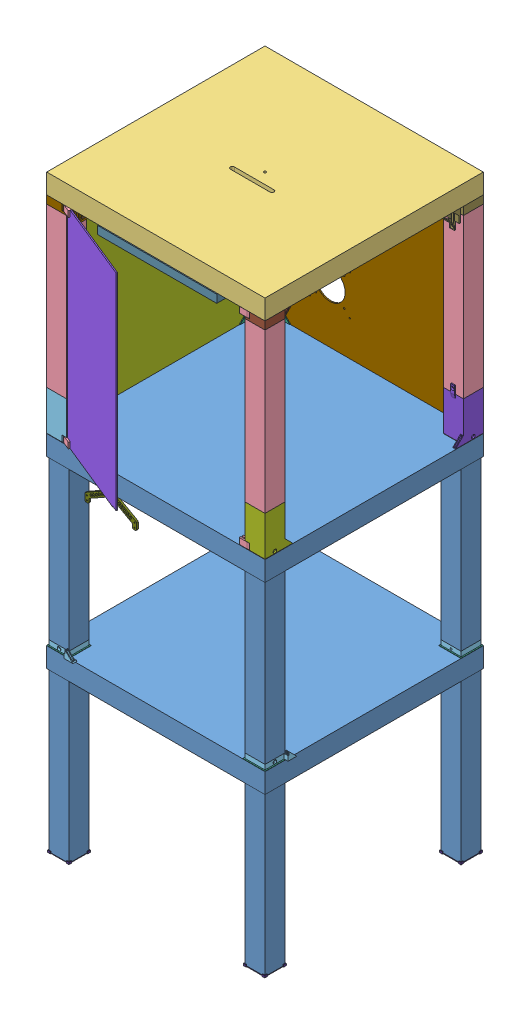
SolidWorks assembly Lack_Enclousure, configuration Predeterminado. Lengths in mm.
Overall size (564.62 1485.45 641.06).
45 component instances, 27 part files, 74 mates.
Components (placement in the parent):
- Lack_table_v3-1: Lack_table_v3 [Predeterminado] at (-27.833 176.929 550) size (550 450 550)
- Lack_table_v3-2: Lack_table_v3 [Predeterminado] at (-27.833 639.729 550) size (550 450 550)
- PSU_Holder-1: PSU_Holder [Predeterminado] at (-246.7267 603.8361 312.8336) x (0.000912 0.040041 0.999198) z (-0.058524 -0.997483 0.040025) size (59 110.01 50)
- Mesa_3-1: Mesa_3 [Predeterminado] at (23.6993 1810.529 527.7704) x (1 0 0) z (0 -1 0) size (550 558.12 570)
  - Table_Top-1: Table_Top [Predeterminado] at (-92.521 118.644 550) size (550 550 50)
  - Table_Leg-1: Table_Leg [Predeterminado] at (193.9079 -225.7264 620) size (50 50 400)
  - Table_Leg-2: Table_Leg [Predeterminado] at (-299.4883 -223.2106 620) x (0 -1 0) z (0 0 1) size (50 50 400)
  - Table_Leg-3: Table_Leg [Predeterminado] at (-296.9726 270.1856 620) x (-1 0 0) z (0 0 1) size (50 50 400)
  - Table_Leg-4: Table_Leg [Predeterminado] at (196.4237 267.6699 620) x (0 1 0) z (0 0 1) size (50 50 400)
  - Bottom_Leg_Left-1: Bottom_Leg_Left [Predeterminado] at (-301.5323 272.2296 1020) size (52.6 70 120)
  - Bottom_Leg_Back-1: Bottom_Leg_Back [Predeterminado] at (-301.5323 -227.7704 1020) size (70 70 120)
  - SimetríaBottom_Leg_Left-5: SimetríaBottom_Leg_Left [Predeterminado] at (198.4677 272.2296 1020) x (-1 0 0) z (0 0 -1) size (52.6 70 120)
  - SimetríaBottom_Leg_Back-3: SimetríaBottom_Leg_Back [Predeterminado] at (198.4677 -227.7704 1020) x (-1 0 0) z (0 0 -1) size (70 70 120)
  - Top_Front-2: Top_Front [Predeterminado] at (-301.5323 272.2296 600) size (114 114 61)
  - Top_Back-2: Top_Back [Predeterminado] at (-301.5323 -227.7704 600) x (0 1 0) z (0 0 1) size (114 114 61)
  - SimetríaTop_Front-3: SimetríaTop_Front [Predeterminado] at (198.4677 272.2296 600) x (-1 0 0) z (0 0 -1) size (114 114 61)
  - SimetríaTop_Back-3: SimetríaTop_Back [Predeterminado] at (198.4677 -227.7704 600) x (0 1 0) z (0 0 -1) size (114 114 61)
  - Plexi_Holder-1: Plexi_Holder [Predeterminado] at (172.5677 -250.9704 600) x (-1 0 0) z (0 -1 0) size (25.9 25 15.72)
- Draft_Sheet_Holder-1: Draft_Sheet_Holder [Predeterminado] at (-133.7686 1178.8709 485) size (300 20 340)
- LCD_Holder_base-1: LCD_Holder_base [Predeterminado] at (-144.833 639.729 703) size (20 10 122)
- LCD_Holder-1: LCD_Holder [Predeterminado] at (-144.4943 635.2142 806.9182) size (130 49 15)
- Bottom_Feet-1: Bottom_Feet [Predeterminado] at (-275.083 -224.271 796.75) x (1 0 0) z (0 1 0) size (54.1 54.1 30.5)
- Bottom_Feet-2: Bottom_Feet [Predeterminado] at (218.917 -224.271 797.25) x (0 0 -1) z (0 1 0) size (54.1 54.1 30.5)
- Bottom_Feet-3: Bottom_Feet [Predeterminado] at (219.417 -224.271 303.25) x (-1 0 0) z (0 1 0) size (54.1 54.1 30.5)
- Bottom_Feet-4: Bottom_Feet [Predeterminado] at (-274.583 -224.271 302.75) x (0 0 1) z (0 1 0) size (54.1 54.1 30.5)
- Bottom_Back-1: Bottom_Back [Predeterminado] at (-277.833 689.729 300) x (1 0 0) z (0 1 0) size (50 50 10.8)
- Bottom_Door-1: Bottom_Door [Predeterminado] at (-277.833 689.729 800) x (1 0 0) z (0 1 0) size (50 50 15.8)
- SimetríaBottom_Door-2: SimetríaBottom_Door [Predeterminado] at (222.167 689.729 800) x (-1 0 0) z (0 -1 0) size (50 50 15.8)
- SimetríaBottom_Back-2: SimetríaBottom_Back [Predeterminado] at (222.167 689.729 300) x (-1 0 0) z (0 -1 0) size (50 50 10.8)
- Bottom_Hinge-1: Bottom_Hinge [Predeterminado] at (-258.033 690.529 819.8) x (0.926121 0 0.377228) z (0 1 0) size (25.2 10.4 15)
- Bottom_Hinge-2: Bottom_Hinge [Predeterminado] at (202.367 690.529 819.8) x (-1 0 0) z (0 1 0) size (25.2 10.4 15)
- Table_Union_Bottom-1: Table_Union_Bottom [Predeterminado] at (-274.833 239.729 797) x (0 0 -1) z (0 -1 0) size (60.05 70 20)
- Bottom_Table_2-1: Bottom_Table_2 [Predeterminado] at (-274.833 226.929 797) x (0 0 -1) z (0 1 0) size (56 56 10.8)
- Bottom_Table_2-2: Bottom_Table_2 [Predeterminado] at (219.167 226.929 797) x (-1 0 0) z (0 1 0) size (56 56 10.8)
- Bottom_Table_2-3: Bottom_Table_2 [Predeterminado] at (219.167 226.929 303) x (0 0 1) z (0 1 0) size (56 56 10.8)
- Bottom_Table_2-4: Bottom_Table_2 [Predeterminado] at (-274.833 226.929 303) x (1 0 0) z (0 1 0) size (56 56 10.8)
- Table_Union_Bottom-5: Table_Union_Bottom [Predeterminado] at (219.167 239.729 797) x (-1 0 0) z (0 -1 0) size (60.05 70 20)
- Table_Union_Bottom-6: Table_Union_Bottom [Predeterminado] at (219.167 239.729 303) x (0 0 1) z (0 -1 0) size (60.05 70 20)
- Table_Union_Bottom-7: Table_Union_Bottom [Predeterminado] at (-274.833 239.729 303) x (1 0 0) z (0 -1 0) size (60.05 70 20)
- Bottom_Hinge-3: Bottom_Hinge [Predeterminado] at (-258.0302 1210.329 819.8028) x (0.926121 0 0.377228) z (0 -1 0) size (25.2 10.4 15)
- Bottom_Hinge-4: Bottom_Hinge [Predeterminado] at (202.3643 1210.329 819.8028) x (-1 0 0) z (0 -1 0) size (25.2 10.4 15)
- Plexi_Sides-1: Plexi_Sides [Predeterminado] at (-300.683 886.8257 513.1613) x (0 0 -1) z (1 0 0) size (450 520.8 3)
- Plexi_Holder-1: Plexi_Holder [Predeterminado] at (-300.483 1210.529 326) x (0 0 1) z (-1 0 0) size (25.9 25 15.72)
- Plexi_Door-3: Plexi_Door [Predeterminado] at (-31.0427 914.3974 910.5317) x (0.926121 0 0.377228) z (-0.377228 0 0.926121) size (222.7 520.8 3)
- Plexi_Back_80-1: Plexi_Back_80 [Predeterminado] at (9.0057 886.8257 276.95) size (450 520.8 3)
Mates (geometry in assembly coordinates):
- Coincidente7: coincident anti-aligned: plane of Lack_table_v3-2 through (-27.833 689.729 550) normal (0 1 0); plane of Bottom_lower-1 through (189.0824 676.929 768.5511) normal (0 -1 0)
- Tangente1: tangent aligned: plane of Lack_table_v3-2 through (-302.833 639.729 825) normal (0 0 1); face of ?
- Tangente2: tangent aligned: plane of Lack_table_v3-2 through (247.167 639.729 825) normal (1 0 0); edge_curve of ?
- Coincidente8: coincident anti-aligned: plane of Lack_table_v3-2 through (-27.833 689.729 550) normal (0 1 0); plane of Bottom_lower-2 through (-309.2819 676.929 833.0846) normal (0 -1 0)
- Tangente3: tangent aligned: plane of Lack_table_v3-2 through (-302.833 639.729 825) normal (0 0 1); edge_curve of ?
- Tangente4: tangent aligned: plane of Lack_table_v3-2 through (-302.833 639.729 275) normal (-1 0 0); edge_curve of ?
- Coincidente11: coincident anti-aligned: plane of Bottom_lower-2 through (-309.2819 677.929 833.0846) normal (0 1 0); plane of Mesa_3-1/Bottom_Top_Door_Left-1 through (-309.083 677.929 831.25) normal (0 -1 0)
- Coincidente16: coincident aligned: plane of Lack_table_v3-2 through (-302.833 639.729 825) normal (0 0 1); plane of Mesa_3-1/Table_Leg-3 through (-252.833 790.529 825) normal (0 0 1)
- Coincidente17: coincident aligned: plane of Lack_table_v3-2 through (-302.833 639.729 275) normal (-1 0 0); plane of Mesa_3-1/Table_Leg-3 through (-302.833 790.529 775) normal (-1 0 0)
- Coincidente18: coincident anti-aligned: plane of Mesa_3-1/Table_Top-1 through (-68.8217 1260.529 646.4143) normal (0 1 0); plane of Spool_Holder_Base-1 through (-96.2362 1260.529 455.3709) normal (0 -1 0)
- Bloquear1: lock: unknown of Mesa_3-1/Table_Top-1; unknown of Spool_Holder_Base-1
- Coincidente24: coincident anti-aligned: plane of Lack_table_v3-2 through (-27.833 639.729 550) normal (0 -1 0); plane of LCD_Holder_base-1 through (-154.833 639.729 823) normal (0 1 0)
- Coincidente25: coincident aligned: plane of Lack_table_v3-2 through (-302.833 639.729 825) normal (0 0 1); plane of LCD_Holder_base-1 through (-144.833 639.729 825) normal (0 0 1)
- Distancia2: distance = 95 mm anti-aligned: plane of LCD_Holder_base-1 through (-154.833 639.729 823) normal (-1 0 0); plane of Lack_table_v3-2 through (-249.833 639.729 772) normal (1 0 0)
- Coincidente29: coincident aligned: plane of Mesa_3-1/Table_Top-1 through (-302.833 1210.529 825) normal (0 0 1); plane of Draft_Sheet_Holder-1 through (-133.7686 1178.8709 825) normal (0 0 1)
- Coincidente30: coincident anti-aligned: plane of LCD_Holder_base-1 through (-154.833 630.729 823) normal (0 -1 0); plane of LCD_Holder-1 through (-155.033 630.729 821.9182) normal (0 1 0)
- Distancia3: distance = 0.2 mm anti-aligned: plane of LCD_Holder-1 through (-134.5501 630.729 821.9182) normal (-0.707107 -0.707107 0); plane of LCD_Holder_base-1 through (-134.833 630.729 823) normal (0.707107 0.707107 0)
- Distancia límite1: limit distance = 1.0818 mm anti-aligned: plane of LCD_Holder-1 through (-144.4943 635.2142 821.9182) normal (0 0 1); plane of LCD_Holder_base-1 through (-144.833 639.729 823) normal (0 0 -1)
- Coincidente31: coincident anti-aligned: plane of Lack_table_v3-1 through (-274.833 -223.071 797) normal (0 -1 0); plane of Bottom_Feet-1 through (-275.083 -223.071 796.75) normal (0 1 0)
- Coincidente32: coincident anti-aligned: plane of Lack_table_v3-1 through (-249.833 176.929 822) normal (0 0 1); plane of Bottom_Feet-1 through (-249.833 -219.271 822) normal (0 0 -1)
- Coincidente33: coincident anti-aligned: plane of Lack_table_v3-1 through (-249.833 176.929 772) normal (1 0 0); plane of Bottom_Feet-1 through (-249.833 -219.271 817) normal (-1 0 0)
- Coincidente34: coincident anti-aligned: plane of Lack_table_v3-2 through (-27.833 689.729 550) normal (0 1 0); plane of Bottom_Back-1 through (-277.833 689.729 300) normal (0 -1 0)
- Coincidente35: coincident aligned: plane of Lack_table_v3-2 through (-302.833 639.729 275) normal (-1 0 0); plane of Bottom_Back-1 through (-302.833 690.529 325) normal (-1 0 0)
- Coincidente36: coincident aligned: plane of Lack_table_v3-2 through (247.167 639.729 275) normal (0 0 -1); plane of Bottom_Back-1 through (-252.833 690.529 275) normal (0 0 -1)
- Coincidente37: coincident anti-aligned: plane of Lack_table_v3-2 through (-27.833 689.729 550) normal (0 1 0); plane of Bottom_Door-1 through (-277.833 689.729 800) normal (0 -1 0)
- Coincidente38: coincident aligned: plane of Lack_table_v3-2 through (-302.833 639.729 275) normal (-1 0 0); plane of Bottom_Door-1 through (-302.833 690.529 825) normal (-1 0 0)
- Coincidente39: coincident aligned: plane of Lack_table_v3-2 through (-302.833 639.729 825) normal (0 0 1); plane of Bottom_Door-1 through (-252.833 690.529 825) normal (0 0 1)
- Coincidente41: coincident anti-aligned: plane of Mesa_3-1/Bottom_Leg_Left-1 through (-277.833 690.529 800) normal (0 -1 0); plane of Bottom_Door-1 through (-277.833 690.529 800) normal (0 1 0)
- Coincidente42: coincident anti-aligned: plane of Bottom_Door-1 through (-277.833 690.529 800) normal (0 1 0); plane of Bottom_Hinge-1 through (-258.033 690.529 819.8) normal (0 -1 0)
- Concéntrica1: concentric aligned: cylinder of Bottom_Door-1 through (-258.033 705.529 819.8) axis (0 -1 0) radius 3; cylinder of Bottom_Hinge-1 through (-258.033 705.529 819.8) axis (0 -1 0) radius 3.1
- Coincidente43: coincident anti-aligned: plane of SimetríaBottom_Door-2 through (222.167 690.529 800) normal (0 1 0); plane of Bottom_Hinge-2 through (202.367 690.529 819.8) normal (0 -1 0)
- Concéntrica4: concentric aligned: cylinder of SimetríaBottom_Door-2 through (202.367 705.529 819.8) axis (0 -1 0) radius 3; cylinder of Bottom_Hinge-2 through (202.367 705.529 819.8) axis (0 -1 0) radius 3.1
- Coincidente44: coincident anti-aligned: plane of Lack_table_v3-1 through (-27.833 226.929 550) normal (0 1 0); plane of Bottom_Back-2 through (-277.833 226.929 800) normal (0 -1 0)
- Coincidente45: coincident aligned: plane of Lack_table_v3-1 through (-302.833 176.929 825) normal (0 0 1); plane of Bottom_Back-2 through (-252.833 227.729 825) normal (0 0 1)
- Coincidente46: coincident aligned: plane of Lack_table_v3-1 through (-302.833 176.929 275) normal (-1 0 0); plane of Bottom_Back-2 through (-302.833 227.729 775) normal (-1 0 0)
- Coincidente47: coincident anti-aligned: plane of Lack_table_v3-2 through (-274.833 239.729 797) normal (0 -1 0); plane of Table_Union_Bottom-1 through (-274.833 239.729 797) normal (0 1 0)
- Coincidente48: coincident aligned: plane of Lack_table_v3-2 through (-249.833 639.729 822) normal (0 0 1); plane of Table_Union_Bottom-1 through (-299.833 227.729 822) normal (0 0 1)
- Coincidente49: coincident aligned: plane of Lack_table_v3-2 through (-299.833 639.729 822) normal (-1 0 0); plane of Table_Union_Bottom-1 through (-299.833 227.729 772) normal (-1 0 0)
- Coincidente50: coincident anti-aligned: plane of Bottom_Back-2 through (-277.833 227.729 800) normal (0 1 0); plane of Table_Union_Bottom-1 through (-274.833 227.729 797) normal (0 -1 0)
- Coincidente53: coincident aligned: plane of Lack_table_v3-1 through (-302.833 176.929 825) normal (0 0 1); plane of Lack_table_v3-2 through (-302.833 639.729 825) normal (0 0 1)
- Coincidente54: coincident aligned: plane of Lack_table_v3-1 through (-302.833 176.929 275) normal (-1 0 0); plane of Lack_table_v3-2 through (-302.833 639.729 275) normal (-1 0 0)
- Coincidente55: coincident anti-aligned: plane of Lack_table_v3-1 through (-27.833 226.929 550) normal (0 1 0); plane of Bottom_Table_2-1 through (-274.833 226.929 797) normal (0 -1 0)
- Coincidente56: coincident aligned: plane of Lack_table_v3-1 through (-302.833 176.929 825) normal (0 0 1); plane of Bottom_Table_2-1 through (-246.833 227.729 825) normal (0 0 1)
- Coincidente57: coincident aligned: plane of Lack_table_v3-1 through (-302.833 176.929 275) normal (-1 0 0); plane of Bottom_Table_2-1 through (-302.833 227.729 769) normal (-1 0 0)
- Coincidente58: coincident anti-aligned: plane of Table_Union_Bottom-1 through (-274.833 227.729 797) normal (0 -1 0); plane of Bottom_Table_2-1 through (-274.833 227.729 797) normal (0 1 0)
- Coincidente59: coincident aligned: plane of Lack_table_v3-1 through (-249.833 176.929 822) normal (0 0 1); plane of Lack_table_v3-2 through (-249.833 639.729 822) normal (0 0 1)
- Coincidente60: coincident aligned: plane of Lack_table_v3-1 through (-299.833 176.929 822) normal (-1 0 0); plane of Lack_table_v3-2 through (-299.833 639.729 822) normal (-1 0 0)
- Coincidente61: coincident anti-aligned: plane of Mesa_3-1/Top_Front-2 through (-258.833 1195.329 819) normal (0 1 0); plane of Bottom_Hinge-3 through (-258.0302 1195.329 819.8028) normal (0 -1 0)
- Concéntrica5: concentric anti-aligned: cylinder of Mesa_3-1/Top_Front-2 through (-258.0302 1195.329 819.8028) axis (0 1 0) radius 3; circle of Bottom_Hinge-3
- Coincidente62: coincident anti-aligned: plane of Mesa_3-1/SimetríaTop_Front-3 through (203.167 1195.329 819) normal (0 1 0); plane of Bottom_Hinge-4 through (202.3643 1195.329 819.8028) normal (0 -1 0)
- Concéntrica6: concentric aligned: cylinder of Mesa_3-1/SimetríaTop_Front-3 through (202.3643 1195.329 819.8028) axis (0 1 0) radius 3; cylinder of Bottom_Hinge-4 through (202.3643 1195.329 819.8028) axis (0 1 0) radius 3.1
- Coincidente63: coincident anti-aligned: plane of Bottom_Hinge-3 through (-238.9797 1223.1388 826.0507) normal (-0.377228 0 0.926121); plane of Plexi_Door-1
- Coincidente64: coincident anti-aligned: plane of Bottom_Hinge-3 through (-258.0302 1208.329 819.8028) normal (0 -1 0); plane of Plexi_Door-1 through (-255.0073 1208.329 824.8409) normal (0 1 0)
- Coincidente65: coincident anti-aligned: plane of Bottom_Hinge-3 through (-250.5562 1223.1388 821.3354) normal (0.926121 0 0.377228); plane of Plexi_Door-1
- Coincidente66: coincident anti-aligned: plane of Mesa_3-1/Bottom_Leg_Back-1 through (-297.683 790.529 300) normal (-1 0 0); plane of Plexi_Sides-1 through (-297.683 886.8257 513.1613) normal (1 0 0)
- Coincidente67: coincident anti-aligned: plane of Mesa_3-1/Bottom_Leg_Left-1 through (-252.833 690.529 775) normal (0 0 -1); plane of Plexi_Sides-1 through (-297.683 1185.529 775) normal (0 0 1)
- Coincidente68: coincident anti-aligned: plane of Mesa_3-1/Table_Top-1 through (-68.8217 1210.529 646.4143) normal (0 -1 0); plane of Plexi_Sides-1 through (-297.683 1210.529 774) normal (0 1 0)
- Coincidente69: coincident anti-aligned: plane of Bottom_Hinge-1 through (-238.9824 677.7193 826.048) normal (-0.377228 0 0.926121); plane of Plexi_Door-1
- Coincidente70: coincident anti-aligned: plane of Bottom_Hinge-4 through (182.3643 1223.1388 818.4028) normal (0 0 1); plane of Plexi_Door-2 through (27.9874 914.3974 991.9522) normal (-0.707107 0 -0.707107)
- Coincidente71: coincident anti-aligned: plane of Bottom_Hinge-4 through (202.3643 1208.329 819.8028) normal (0 -1 0); plane of Plexi_Door-2 through (197.2201 1208.329 822.7196) normal (0 1 0)
- Coincidente72: coincident anti-aligned: plane of Bottom_Hinge-4 through (194.8643 1223.1388 821.2028) normal (-1 0 0); plane of Plexi_Door-2 through (197.2201 1196.329 822.7196) normal (0.707107 0 -0.707107)
- Coincidente73: coincident anti-aligned: plane of Bottom_Hinge-2 through (182.367 677.7193 818.4) normal (0 0 1); plane of Plexi_Door-2 through (27.9874 914.3974 991.9522) normal (-0.707107 0 -0.707107)
- Coincidente75: coincident anti-aligned: plane of Plexi_Sides-1 through (-297.683 1210.529 326) normal (0 0 -1); plane of Plexi_Holder-1 through (-300.483 1210.529 326) normal (0 0 1)
- Coincidente76: coincident aligned: plane of Plexi_Sides-1 through (-297.683 1210.529 774) normal (0 1 0); plane of Plexi_Holder-1 through (-302.283 1210.529 326) normal (0 1 0)
- Coincidente77: coincident anti-aligned: plane of Plexi_Sides-1 through (-297.683 886.8257 513.1613) normal (1 0 0); plane of Plexi_Holder-1 through (-297.683 1210.529 326) normal (-1 0 0)
- Paralelo6: parallel aligned: plane of Bottom_Hinge-1 through (-237.549 705.529 822.5287) normal (0.926121 0 0.377228); plane of Bottom_Hinge-3 through (-241.4694 1195.329 832.1631) normal (0.926121 0 0.377228)
- Paralelo7: parallel aligned: plane of Bottom_Hinge-2 through (182.367 705.529 825) normal (-1 0 0); plane of Bottom_Hinge-4 through (182.3643 1195.329 814.6028) normal (-1 0 0)
- Ángulo límite1: limit planar angle = 1.183995 rad anti-aligned: plane of Bottom_Hinge-3 through (-259.9918 1195.329 824.6186) normal (-0.377228 0 0.926121); plane of Mesa_3-1/Top_Front-2 through (-263.833 1195.329 819) normal (1 0 0)
- Coincidente85: coincident anti-aligned: plane of Bottom_Hinge-3 through (-250.5562 1223.1388 821.3354) normal (0.926121 0 0.377228); plane of Plexi_Door-3 through (-251.6124 1208.329 823.9285) normal (-0.926121 0 -0.377228)
- Coincidente86: coincident anti-aligned: plane of Bottom_Hinge-3 through (-258.0302 1208.329 819.8028) normal (0 -1 0); plane of Plexi_Door-3 through (-251.6124 1208.329 823.9285) normal (0 1 0)
- Coincidente87: coincident anti-aligned: plane of Bottom_Hinge-3 through (-240.0359 1223.1388 828.6439) normal (0.377228 0 -0.926121); plane of Plexi_Door-3 through (-32.1744 914.3974 913.31) normal (-0.377228 0 0.926121)
- Coincidente88: coincident anti-aligned: plane of Mesa_3-1/Bottom_Leg_Back-1 through (-277.833 790.529 276.95) normal (0 0 1); plane of Plexi_Back_80-1 through (9.0057 886.8257 276.95) normal (0 0 -1)
- Coincidente89: coincident anti-aligned: plane of Mesa_3-1/Table_Top-1 through (-68.8217 1210.529 646.4143) normal (0 -1 0); plane of Plexi_Back_80-1 through (-251.833 1210.529 279.95) normal (0 1 0)
- Coincidente90: coincident anti-aligned: plane of Mesa_3-1/SimetríaBottom_Leg_Back-3 through (197.167 690.529 275) normal (-1 0 0); plane of Plexi_Back_80-1 through (197.167 1185.529 279.95) normal (1 0 0)
